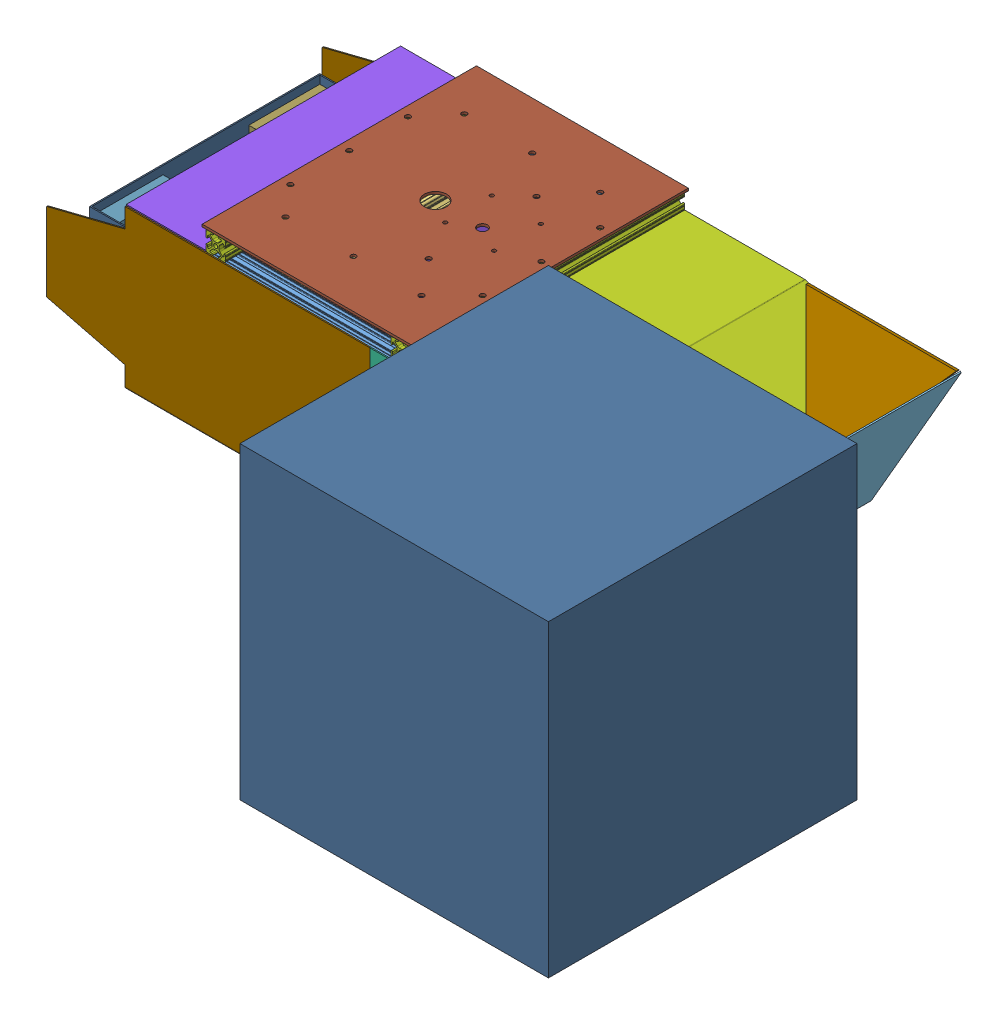
SolidWorks assembly Assembly, configuration Default. Lengths in mm.
Overall size (1112.63 475.22 820.95).
54 component instances, 32 part files, 46 mates.
Components (placement in the parent):
- Chassis-1: Chassis [Default] at (103.7394 -95.2112 114.6458) size (508 203.2 355.6)
  - 8020_20-2: 8020_20 [Default<As Machined>] at (120.0745 290.6035 409.3079) size (508 25.4 25.4)
  - 8020_20-3: 8020_20 [Default<As Machined>] at (120.0745 290.6035 79.1079) size (508 25.4 25.4)
  - 8020_20-4: 8020_20 [Default<As Machined>] at (120.0745 468.4035 409.3079) size (508 25.4 25.4)
  - 8020_20-5: 8020_20 [Default<As Machined>] at (120.0745 468.4035 79.1079) size (508 25.4 25.4)
  - 8020_06-2: 8020_06 [Default<As Machined>] at (170.8745 379.5035 79.1079) x (1 0 0) z (0 1 0) size (25.4 25.4 152.4)
  - 8020_06-3: 8020_06 [Default<As Machined>] at (335.9745 379.5035 409.3079) x (1 0 0) z (0 1 0) size (25.4 25.4 152.4)
  - 8020_06-4: 8020_06 [Default<As Machined>] at (335.9745 379.5035 79.1079) x (1 0 0) z (0 1 0) size (25.4 25.4 152.4)
  - 8020_06-5: 8020_06 [Default<As Machined>] at (170.8745 379.5035 409.3079) x (1 0 0) z (0 1 0) size (25.4 25.4 152.4)
  - 8020_12-2: 8020_12 [Default<As Machined>] at (196.2745 290.6035 244.2079) size (25.4 25.4 304.8)
  - 8020_12-3: 8020_12 [Default<As Machined>] at (43.8745 290.6035 244.2079) size (25.4 25.4 304.8)
  - 8020_06-6: 8020_06 [Default<As Machined>] at (-95.8255 379.5035 79.1079) x (1 0 0) z (0 -1 0) size (25.4 25.4 152.4)
  - 8020_06-7: 8020_06 [Default<As Machined>] at (69.2745 379.5035 79.1079) x (1 0 0) z (0 -1 0) size (25.4 25.4 152.4)
  - 8020_06-8: 8020_06 [Default<As Machined>] at (69.2745 379.5035 409.3079) x (1 0 0) z (0 -1 0) size (25.4 25.4 152.4)
  - 8020_06-9: 8020_06 [Default<As Machined>] at (-95.8255 379.5035 409.3079) x (1 0 0) z (0 -1 0) size (25.4 25.4 152.4)
  - 8020_12-4: 8020_12 [Default<As Machined>] at (196.2745 468.4035 244.2079) size (25.4 25.4 304.8)
  - 8020_12-5: 8020_12 [Default<As Machined>] at (43.8745 468.4035 244.2079) size (25.4 25.4 304.8)
- Analysis_Plate-1: Analysis_Plate [Default] at (446.0639 185.8674 358.8537) x (-0.240322 0 0.970693) z (-0.970693 0 -0.240322) size (254 3.17 254)
- Fairing-1: Fairing [Default] at (287.3139 181.1049 181.0537) x (0 0 -1) z (1 0 0) size (355.6 203.99 409.42)
- Left_Panel-2: Left_Panel [Default] at (286.3974 182.6924 179.4662) x (-1 0 0) z (0 0 -1) size (409.57 204.1 50.95) (hidden)
- Right_Panel-1: Right_Panel [Default] at (286.3974 182.6924 536.6537) x (-1 0 0) z (0 0 -1) size (409.57 204.1 50.95)
- Upper_Fairing-2: Upper_Fairing [Default] at (338.1181 385.8924 536.6537) x (0 0 -1) z (1 0 0) size (355.6 77.4 322.38)
- Right_Slope-1: Right_Slope [Default] at (498.5881 385.8924 536.6537) x (0 0 -1) z (1 0 0) size (166.12 59.31 195.41)
- Left_Slope-1: Left_Slope [Default] at (498.5881 385.8924 485.8537) x (0 0 -1) z (1 0 0) size (166.12 59.31 195.41)
- Electronics-1: Electronics [Default] at (-948.2867 852.3901 -9.3563) x (0 0 1) z (-1 0 0) size (298.45 107.88 685.8)
  - Copy of Electronics.CATProduct^Electronics-1: Copy of Electronics.CATProduct^Electronics [Default] at origin size (298.45 107.88 685.8) (virtual)
    - Copy of Box_Layout_V2.CATProduct^Copy of Electronics.CATProduct_Electronics-1: Copy of Box_Layout_V2.CATProduct^Copy of Electronics.CATProduct_Electronics [Default] at origin size (298.45 107.88 685.8) (virtual)
      - Copy of Enclosure2.CATPart^Copy of Box_Layout_V2.CATProduct_Copy of Electronics.CATProduct_Electronics-1: Copy of Enclosure2.CATPart^Copy of Box_Layout_V2.CATProduct_Copy of Electronics.CATProduct_Electronics [Default] at (517.435 -623.6476 -841.9006) size (298.45 107.88 685.8) (virtual)
      - Copy of Contact_Block.CATPart^Copy of Box_Layout_V2.CATProduct_Copy of Electronics.CATProduct_Electronics-1: Copy of Contact_Block.CATPart^Copy of Box_Layout_V2.CATProduct_Copy of Electronics.CATProduct_Electronics [Default] at (379.9575 -622.0601 -1110.1881) size (49.23 47.62 182.56) (virtual)
      - Copy of Fan.CATPart^Copy of Box_Layout_V2.CATProduct_Copy of Electronics.CATProduct_Electronics-1: Copy of Fan.CATPart^Copy of Box_Layout_V2.CATProduct_Copy of Electronics.CATProduct_Electronics [Default] at (423.8487 -622.0601 -1526.1131) size (92 92 25.4) (virtual)
      - Copy of USB_hub.CATPart^Copy of Box_Layout_V2.CATProduct_Copy of Electronics.CATProduct_Electronics-1: Copy of USB_hub.CATPart^Copy of Box_Layout_V2.CATProduct_Copy of Electronics.CATProduct_Electronics [Default] at (505.6875 -622.0601 -1241.2331) x (0 -1 0) z (0 0 1) size (30.48 10.16 106.68) (virtual)
      - Copy of Fan_1.CATPart^Copy of Box_Layout_V2.CATProduct_Copy of Electronics.CATProduct_Electronics-1: Copy of Fan_1.CATPart^Copy of Box_Layout_V2.CATProduct_Copy of Electronics.CATProduct_Electronics [Default] at (423.8487 -530.0613 -843.4881) x (1 0 0) z (0 0 -1) size (92 92 25.4) (virtual)
      - Copy of Fan.CATPart^Copy of Box_Layout_V2.CATProduct_Copy of Electronics.CATProduct_Electronics-2: Copy of Fan.CATPart^Copy of Box_Layout_V2.CATProduct_Copy of Electronics.CATProduct_Electronics [Default] at (220.5725 -622.0601 -868.8881) size (92 92 25.4) (virtual)
      - Copy of Network_Switch.CATPart^Copy of Box_Layout_V2.CATProduct_Copy of Electronics.CATProduct_Electronics-1: Copy of Network_Switch.CATPart^Copy of Box_Layout_V2.CATProduct_Copy of Electronics.CATProduct_Electronics [Default] at (515.8475 -622.0601 -1373.3131) x (0 0 1) z (0 -1 0) size (102.71 26.76 95.42) (virtual)
      - Copy of USB_hub.CATPart^Copy of Box_Layout_V2.CATProduct_Copy of Electronics.CATProduct_Electronics-2: Copy of USB_hub.CATPart^Copy of Box_Layout_V2.CATProduct_Copy of Electronics.CATProduct_Electronics [Default] at (515.8475 -591.5801 -1109.1531) x (0 1 0) z (0 0 1) size (30.48 10.16 106.68) (virtual)
      - Copy of USB_hub.CATPart^Copy of Box_Layout_V2.CATProduct_Copy of Electronics.CATProduct_Electronics-3: Copy of USB_hub.CATPart^Copy of Box_Layout_V2.CATProduct_Copy of Electronics.CATProduct_Electronics [Default] at (230.7325 -591.5801 -1038.4331) x (0 1 0) z (0 0 1) size (30.48 10.16 106.68) (virtual)
      - Copy of 12V_Regulator.CATPart^Copy of Box_Layout_V2.CATProduct_Copy of Electronics.CATProduct_Electronics-1: Copy of 12V_Regulator.CATPart^Copy of Box_Layout_V2.CATProduct_Copy of Electronics.CATProduct_Electronics [Default] at (220.5725 -522.1876 -1186.3881) x (0 0 1) z (0 1 0) size (85.72 30.48 47.62) (virtual)
      - Copy of Breaker.CATPart^Copy of Box_Layout_V2.CATProduct_Copy of Electronics.CATProduct_Electronics-1: Copy of Breaker.CATPart^Copy of Box_Layout_V2.CATProduct_Copy of Electronics.CATProduct_Electronics [Default] at (256.1325 -622.0601 -1110.1881) size (85.72 79.38 157.16) (virtual)
      - Copy of 24V_Converter.CATPart^Copy of Box_Layout_V2.CATProduct_Copy of Electronics.CATProduct_Electronics-1: Copy of 24V_Converter.CATPart^Copy of Box_Layout_V2.CATProduct_Copy of Electronics.CATProduct_Electronics [Default] at (252.3225 -522.1876 -878.4004) x (0 1 0) z (0 0 1) size (76.2 31.75 74.63) (virtual)
      - Copy of 5V_Converter.CATPart^Copy of Box_Layout_V2.CATProduct_Copy of Electronics.CATProduct_Electronics-1: Copy of 5V_Converter.CATPart^Copy of Box_Layout_V2.CATProduct_Copy of Electronics.CATProduct_Electronics [Default] at (331.6975 -622.0601 -885.5632) size (53.98 19.05 63.75) (virtual)
      - Copy of Arduino.CATPart^Copy of Box_Layout_V2.CATProduct_Copy of Electronics.CATProduct_Electronics-1: Copy of Arduino.CATPart^Copy of Box_Layout_V2.CATProduct_Copy of Electronics.CATProduct_Electronics [Default] at (470.7975 -596.6601 -1475.3131) x (1 0 0) z (0 0 -1) size (53.34 25.4 101.6) (virtual)
      - Copy of Computer_Assembly.CATProduct^Copy of Box_Layout_V2.CATProduct_Copy of Electronics.CATProduct_Electronics-1: Copy of Computer_Assembly.CATProduct^Copy of Box_Layout_V2.CATProduct_Copy of Electronics.CATProduct_Electronics [Default] at (324.6385 -581.5712 -1409.7656) x (0 0 1) z (-1 0 0) size (191.92 84.8 179.22) (virtual)
        - Copy of Computer.CATPart^Copy of Computer_Assembly.CATProduct_Copy of Box_Layout_V2.CATProduct_Copy of Electronics.CATProduct_Electronics-1: Copy of Computer.CATPart^Copy of Computer_Assembly.CATProduct_Copy of Box_Layout_V2.CATProduct_Copy of Electronics.CATProduct_Electronics [Default] at (67.8025 -40.4888 104.066) size (184.86 83.31 179.22) (virtual)
        - Copy of SSD.CATPart^Copy of Computer_Assembly.CATProduct_Copy of Box_Layout_V2.CATProduct_Copy of Electronics.CATProduct_Electronics-1: Copy of SSD.CATPart^Copy of Computer_Assembly.CATProduct_Copy of Box_Layout_V2.CATProduct_Copy of Electronics.CATProduct_Electronics [Default] at (-116.3475 7.9679 30.2535) x (0 -1 0) z (0 0 1) size (71.27 7.11 100.71) (virtual)
      - Copy of Motor_Controller_Mount.CATPart^Copy of Box_Layout_V2.CATProduct_Copy of Electronics.CATProduct_Electronics-1: Copy of Motor_Controller_Mount.CATPart^Copy of Box_Layout_V2.CATProduct_Copy of Electronics.CATProduct_Electronics [Default] at (500.6075 -622.0601 -1321.3383) x (0 0 -1) z (1 0 0) size (160.35 92.08 243.84) (virtual)
- Chute-1: Chute [Default] at (587.5214 192.1171 373.1412) x (0 0 -1) z (1 0 0) size (41.27 136.87 88.13)
- 8020_14-1: 8020_14 [Default<As Machined>] at (325.4139 398.5924 181.0537) size (25.4 25.4 355.6)
- 8020_14-2: 8020_14 [Default<As Machined>] at (85.7014 398.5924 181.0537) size (25.4 25.4 355.6)
- E-Stop_Mount-1: E-Stop_Mount [Default] at (73.0014 385.8924 181.0537) x (0 0 1) z (-1 0 0) size (355.6 1.59 103.19)
- Rear_Fairing-2: Rear_Fairing [Default] at (-131.8488 233.545 536.6537) x (0 0 -1) z (1 0 0) size (355.6 203.09 103.25) (hidden)
- Battery_Mount-2: Battery_Mount [Default] at (287.3139 181.1049 181.0537) x (0 0 1) z (-1 0 0) size (358.78 204.79 419.1)
- Max_Item_Size-1: Max_Item_Size [Default] at (580.8476 256.3255 1000.4199) size (400 400 400)
- Extreme_Retrieval_Storage-1: Extreme_Retrieval_Storage [Default] at (490.5139 387.4799 181.0537) x (0 0 -1) z (1 0 0) size (355.6 50.8 152.4) (hidden)
- Chassy_Plate-1: Chassy_Plate [Default] at (338.1139 414.4674 200.8975) x (0 0 -1) z (1 0 0) size (355.6 3.17 274.64)
Mates (geometry in assembly coordinates):
- Coincident2: coincident aligned: plane of Chassis-1/8020_20-3 through (477.8139 185.842 181.0537) normal (0 0 -1); plane of Fairing-1 through (578.0721 183.429 181.0537) normal (0 0 -1)
- Width1: width: plane of Chassis-1/8020_20-3 through (477.8139 201.717 181.0537) normal (0 0 -1); plane of Chassis-1/8020_20-2 through (477.8139 204.9428 536.6537) normal (0 0 1); axis of Analysis_Plate-1 through (446.0639 189.0424 358.8537) axis (0 -1 0)
- Distance1: distance = 3.175 mm aligned: plane of Analysis_Plate-1 through (446.0639 185.8674 358.8537) normal (0 -1 0); plane of Chassis-1/8020_20-3 through (477.8139 182.6924 203.3041) normal (0 -1 0)
- Distance2: distance = 133.35 mm: cylinder of Analysis_Plate-1 through (446.0639 189.0424 358.8537) axis (0 -1 0) radius 127; plane of Chassis-1/8020_12-2 through (312.7139 189.0678 206.4537) normal (1 0 0)
- Coincident3: coincident anti-aligned: plane of Chassis-1/8020_20-3 through (477.8139 182.6924 187.4291) normal (0 -1 0); plane of Fairing-1 through (287.3139 182.6924 536.6537) normal (0 1 0)
- Coincident6: coincident aligned: plane of Chassis-1/8020_12-2 through (287.3139 185.842 206.4537) normal (-1 0 0); plane of Fairing-1 through (287.3139 182.6924 536.6537) normal (-1 0 0)
- Coincident7: coincident anti-aligned: plane of Chassis-1/8020_20-3 through (477.8139 185.842 181.0537) normal (0 0 -1); plane of Left_Panel-2 through (286.3974 385.8924 181.0537) normal (0 0 1)
- Coincident8: coincident anti-aligned: plane of Fairing-1 through (578.0391 181.8986 536.6537) normal (-0.866025 0.5 0); plane of Left_Panel-2 through (505.4724 56.2094 179.4662) normal (0.866025 -0.5 0)
- Coincident10: coincident anti-aligned: plane of Fairing-1 through (287.3139 182.6924 536.6537) normal (0 1 0); plane of Left_Panel-2 through (286.3974 182.6924 179.4662) normal (0 -1 0)
- Coincident11: coincident anti-aligned: plane of Chassis-1/8020_20-2 through (477.8139 189.0678 536.6537) normal (0 0 1); plane of Right_Panel-1 through (286.3974 385.8924 536.6537) normal (0 0 -1)
- Coincident12: coincident anti-aligned: plane of Fairing-1 through (578.0391 181.8986 536.6537) normal (-0.866025 0.5 0); plane of Right_Panel-1 through (505.4724 56.2094 536.6537) normal (0.866025 -0.5 0)
- Coincident13: coincident anti-aligned: plane of Fairing-1 through (287.3139 182.6924 536.6537) normal (0 1 0); plane of Right_Panel-1 through (286.3974 182.6924 536.6537) normal (0 -1 0)
- Coincident22: coincident anti-aligned: plane of Chassis-1/8020_20-5 through (477.8139 385.8924 184.2033) normal (0 1 0); plane of Upper_Fairing-2 through (338.1181 385.8924 181.0537) normal (0 -1 0)
- Coincident23: coincident anti-aligned: plane of Left_Panel-2 through (286.3974 385.8924 181.0537) normal (0 0 1); plane of Upper_Fairing-2 through (338.1181 385.8924 181.0537) normal (0 0 -1)
- Coincident32: coincident aligned: plane of Right_Panel-1 through (286.3974 385.8924 536.6537) normal (0 1 0); plane of Right_Slope-1 through (498.5881 385.8924 231.8537) normal (0 1 0)
- Parallel5: parallel aligned: line of Right_Panel-1 through (286.3974 385.8924 536.6537) axis (1 0 0); line of Right_Slope-1 through (498.5881 385.8924 536.6537) axis (1 0 0)
- Coincident35: coincident anti-aligned: plane of Fairing-1 through (578.0391 181.8986 536.6537) normal (-0.866025 0.5 0); plane of Upper_Fairing-2 through (606.2508 230.7627 536.6537) normal (0.866025 -0.5 0)
- Coincident36: coincident: plane of Upper_Fairing-2 through (352.7909 438.9582 536.6537) normal (0.34202 0.939693 0); line of Right_Slope-1 through (498.5881 385.8924 533.4787) axis (0 0 1)
- Coincident37: coincident aligned: line of Right_Panel-1 through (286.3974 385.8924 536.6537) axis (1 0 0); line of Right_Slope-1 through (498.5881 385.8924 536.6537) axis (1 0 0)
- Coincident38: coincident aligned: plane of Left_Panel-2 through (286.3974 385.8924 179.4662) normal (0 1 0); plane of Left_Slope-1 through (498.5881 385.8924 181.0537) normal (0 1 0)
- Coincident39: coincident anti-aligned: plane of Upper_Fairing-2 through (352.7909 438.9582 536.6537) normal (0.34202 0.939693 0); plane of Left_Slope-1 through (661.5281 326.5871 181.0537) normal (-0.34202 -0.939693 0)
- Coincident40: coincident aligned: line of Left_Panel-2 through (286.3974 385.8924 181.0537) axis (1 0 0); line of Left_Slope-1 through (498.5881 385.8924 181.0537) axis (1 0 0)
- Parallel6: parallel anti-aligned: plane of Chassis-1/8020_20-5 through (-30.1861 383.7842 204.3455) normal (-1 0 0); plane of Electronics-1/Copy of Electronics.CATProduct^Electronics-1/Copy of Box_Layout_V2.CATProduct^Copy of Electronics.CATProduct_Electronics-1/Copy of Enclosure2.CATPart^Copy of Box_Layout_V2.CATProduct_Copy of Electronics.CATProduct_Electronics-1 through (579.4139 228.7426 508.0787) normal (1 0 0)
- Width3: width anti-aligned: plane of Chassis-1/8020_20-3 through (477.8139 189.0678 206.4537) normal (0 0 1); plane of Chassis-1/8020_20-2 through (477.8139 185.842 511.2537) normal (0 0 -1); plane of Electronics-1/Copy of Electronics.CATProduct^Electronics-1/Copy of Box_Layout_V2.CATProduct^Copy of Electronics.CATProduct_Electronics-1/Copy of Enclosure2.CATPart^Copy of Box_Layout_V2.CATProduct_Copy of Electronics.CATProduct_Electronics-1 through (579.4139 228.7426 209.6287) normal (0 0 -1); plane of Electronics-1/Copy of Electronics.CATProduct^Electronics-1/Copy of Box_Layout_V2.CATProduct^Copy of Electronics.CATProduct_Electronics-1/Copy of Enclosure2.CATPart^Copy of Box_Layout_V2.CATProduct_Copy of Electronics.CATProduct_Electronics-1 through (-106.3861 228.7426 508.0787) normal (0 0 1)
- Distance8: distance = 20.6502 mm anti-aligned: plane of Electronics-1/Copy of Electronics.CATProduct^Electronics-1/Copy of Box_Layout_V2.CATProduct^Copy of Electronics.CATProduct_Electronics-1/Copy of Enclosure2.CATPart^Copy of Box_Layout_V2.CATProduct_Copy of Electronics.CATProduct_Electronics-1 through (236.5139 228.7426 358.8537) normal (0 -1 0); plane of Chassis-1/8020_12-3 through (138.0635 208.0924 206.4537) normal (0 1 0)
- Distance9: distance = 127 mm aligned: plane of Electronics-1/Copy of Electronics.CATProduct^Electronics-1/Copy of Box_Layout_V2.CATProduct^Copy of Electronics.CATProduct_Electronics-1/Copy of Enclosure2.CATPart^Copy of Box_Layout_V2.CATProduct_Copy of Electronics.CATProduct_Electronics-1 through (579.4139 228.7426 508.0787) normal (1 0 0); plane of Chassis-1/8020_06-3 through (452.4139 208.0924 514.4033) normal (1 0 0)
- Coincident48: coincident anti-aligned: plane of Upper_Fairing-2 through (352.248 437.4665 536.6537) normal (-0.34202 -0.939693 0); plane of Chute-1 through (663.7214 324.0994 344.5662) normal (0.34202 0.939693 0)
- Coincident49: coincident anti-aligned: plane of Upper_Fairing-2 through (604.876 231.5564 536.6537) normal (-0.866025 0.5 0); plane of Chute-1 through (659.2461 325.7283 373.1412) normal (0.866025 -0.5 0)
- Width5: width aligned: plane of Fairing-1 through (389.3246 561.7863 371.5537) normal (0 0 -1); plane of Fairing-1 through (389.3246 561.7863 346.1537) normal (0 0 1); plane of Chute-1 through (568.6392 190.68 371.5537) normal (0 0 -1); plane of Chute-1 through (568.6392 190.68 346.1537) normal (0 0 1)
- Coincident56: coincident anti-aligned: plane of Chassis-1/8020_20-5 through (477.8139 385.8924 184.2033) normal (0 1 0); plane of 8020_14-1 through (315.8635 385.8924 536.6537) normal (0 -1 0)
- Coincident57: coincident aligned: plane of Chassis-1/8020_20-5 through (477.8139 379.517 181.0537) normal (0 0 -1); plane of 8020_14-1 through (336.0057 388.0006 181.0537) normal (0 0 -1)
- Coincident62: coincident anti-aligned: plane of Chassis-1/8020_12-4 through (312.7139 382.7428 206.4537) normal (1 0 0); plane of 8020_14-1 through (312.7139 408.1428 536.6537) normal (-1 0 0)
- Coincident64: coincident anti-aligned: plane of Chassis-1/8020_20-5 through (477.8139 385.8924 184.2033) normal (0 1 0); plane of 8020_14-2 through (92.026 385.8924 536.6537) normal (0 -1 0)
- Coincident65: coincident aligned: plane of Chassis-1/8020_20-5 through (477.8139 379.517 181.0537) normal (0 0 -1); plane of 8020_14-2 through (96.2932 388.0006 181.0537) normal (0 0 -1)
- Coincident71: coincident anti-aligned: plane of Chassis-1/8020_20-5 through (477.8139 385.8924 184.2033) normal (0 1 0); plane of E-Stop_Mount-1 through (73.0014 385.8924 536.6537) normal (0 -1 0)
- Coincident73: coincident anti-aligned: plane of 8020_14-2 through (73.0014 408.1428 536.6537) normal (-1 0 0); plane of E-Stop_Mount-1 through (73.0014 387.4799 536.6537) normal (1 0 0)
- Coincident74: coincident anti-aligned: plane of Chassis-1/8020_20-4 through (-30.1861 383.7842 534.5455) normal (-1 0 0); plane of Rear_Fairing-2 through (-30.1861 233.545 536.6537) normal (1 0 0)
- Coincident76: coincident anti-aligned: plane of E-Stop_Mount-1 through (73.0014 385.8924 536.6537) normal (0 -1 0); plane of Rear_Fairing-2 through (-30.1861 385.8924 536.6537) normal (0 1 0)
- Coincident77: coincident anti-aligned: plane of Chassis-1/8020_20-3 through (477.8139 182.6924 187.4291) normal (0 -1 0); plane of Battery_Mount-2 through (287.3139 182.6924 536.6537) normal (0 1 0)
- Coincident78: coincident anti-aligned: plane of Fairing-1 through (287.3139 182.6924 536.6537) normal (-1 0 0); plane of Battery_Mount-2 through (287.3139 182.6924 536.6537) normal (1 0 0)
- Coincident79: coincident anti-aligned: plane of Chassis-1/8020_20-3 through (477.8139 201.717 181.0537) normal (0 0 -1); plane of Battery_Mount-2 through (287.3139 181.1049 181.0537) normal (0 0 1)
- Coincident80: coincident anti-aligned: plane of Upper_Fairing-2 through (338.1181 387.4799 181.0537) normal (0 1 0); plane of Extreme_Retrieval_Storage-1 through (490.5139 387.4799 181.0537) normal (0 -1 0)
- Coincident81: coincident aligned: plane of 8020_14-1 through (336.0057 388.0006 181.0537) normal (0 0 -1); plane of Extreme_Retrieval_Storage-1 through (490.5139 438.2799 181.0537) normal (0 0 -1)
- Coincident82: coincident anti-aligned: plane of 8020_14-1 through (338.1139 404.917 536.6537) normal (1 0 0); plane of Extreme_Retrieval_Storage-1 through (338.1139 438.2799 181.0537) normal (-1 0 0)
- Coincident83: coincident anti-aligned: plane of 8020_14-1 through (319.0893 411.2924 536.6537) normal (0 1 0); plane of Chassy_Plate-1 through (338.1139 411.2924 200.8975) normal (0 -1 0)
- Coincident85: coincident aligned: plane of 8020_14-1 through (336.0057 388.0006 536.6537) normal (0 0 1); plane of Chassy_Plate-1 through (338.1139 411.2924 536.6537) normal (0 0 1)
